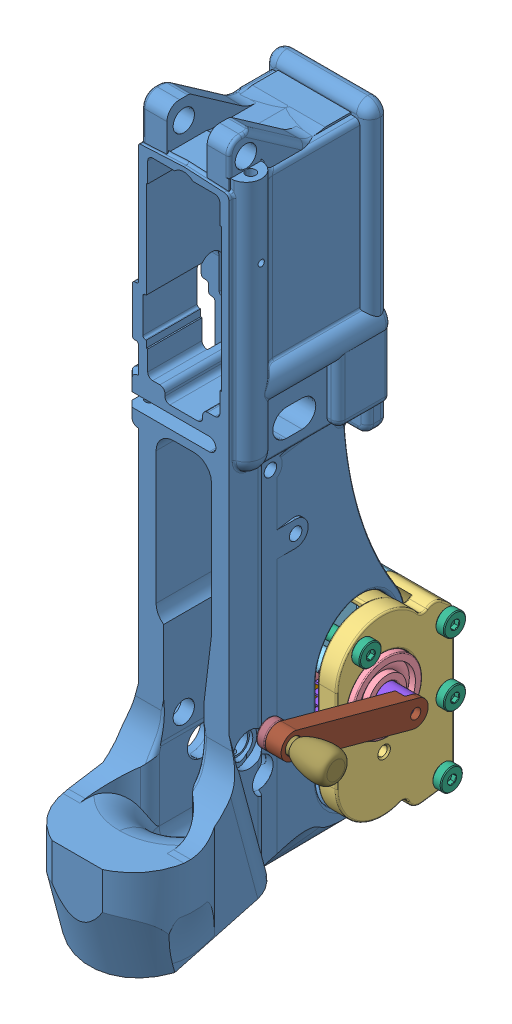
SolidWorks assembly full-assemble, configuration 默认. Lengths in mm.
Overall size (59.29 217.07 108.72).
17 component instances, 13 part files, 43 mates.
Components (placement in the parent):
- MKIIb_Reciever-1: MKIIb_Reciever [默认] at (-34.8208 26.1891 156.3421) size (38.84 217.07 108.72)
- LongTrigger-Straight.step-1: LongTrigger-Straight.step [默认] at (-5.1486 -10.3202 205.3271) x (0 -0.999998 0.002218) z (1 0 0) size (101.01 24.9 16.87)
- Part3-3: Part3 [默认<As Machined>] at (-5.1451 0 0) x (0 0 -1) z (1 0 0) size (37.18 58.07 16)
- instrument ball bearing_68_am-1: instrument ball bearing_68_am [AFBMA 12.1.4.1 - 0080-22 - 8,SI,NC,8_68] at (8.8549 -72.7458 189.2413) x (1 0 0) z (0 -0.317918 0.948118) size (7 22 22)
- Part4-2: Part4 [默认] at (-5.1451 0 0) x (0 0 -1) z (1 0 0) size (37.18 58.07 22.13)
- 92855A428_18-8 Stainless Steel Low-Profile Socket Head Screws-1: 92855A428_18-8 Stainless Steel Low-Profile Socket Head Screws [92855A428] at (-5.2451 -104.2418 170.0652) x (0 -0.350043 -0.936734) z (1 0 0) size (7 7 38.29)
- 92855A428_18-8 Stainless Steel Low-Profile Socket Head Screws-2: 92855A428_18-8 Stainless Steel Low-Profile Socket Head Screws [92855A428] at (-5.2451 -82.3598 169.0652) x (0 -0.001925 -0.999998) z (1 0 0) size (7 7 38.29)
- 92855A428_18-8 Stainless Steel Low-Profile Socket Head Screws-3: 92855A428_18-8 Stainless Steel Low-Profile Socket Head Screws [92855A428] at (-5.2451 -62.3598 169.0652) x (0 0.933702 0.358051) z (1 0 0) size (7 7 38.29)
- 92855A428_18-8 Stainless Steel Low-Profile Socket Head Screws-4: 92855A428_18-8 Stainless Steel Low-Profile Socket Head Screws [92855A428] at (-5.2451 -57.3338 195.7413) x (0 -0.893253 0.449554) z (1 0 0) size (7 7 38.29)
- rod-1: rod [默认] at (-6.6486 -88.4933 194.5525) x (0 -0.97624 -0.216692) z (0 -0.216692 0.97624) size (5 3 19)
- big-gear-4: big-gear [Metric - Spur gear 0.8M 30T 20PA 5.5FW ---S30O3.8H11L0.8N] at (4.3549 -72.7458 189.2413) x (-1 0 0) z (0 -0.965125 0.261791) size (18 25.5 25.6)
- instrument ball bearing_68_am-2: instrument ball bearing_68_am [AFBMA 12.1.4.1 - 0080-22 - 8,SI,NC,8_68] at (-17.6451 -88.7379 188.7413) x (1 0 0) z (0 0.211103 0.977464) size (7 22 22)
- pod-1: pod [默认] at (-21.6486 -88.7379 188.7413) x (0 -0.854815 -0.518933) z (0 -0.518933 0.854815) size (12 15 12)
- hexgon-3: hexgon [Metric - Spur gear 0.8M 10T 20PA 8FW ---S10O3.8H18L0.8N] at (9.3549 -88.7379 188.7413) x (-1 0 0) z (0 -0.518933 0.854815) size (8 12 12)
- crank-3: crank [默认] at (16.3549 -72.7458 189.2413) x (0 0.261791 0.965125) z (0 0.965125 -0.261791) size (47.9 5 7.9)
- handle-3: handle [默认] at (13.3549 -62.2741 227.8463) x (0 -0.8276 -0.561319) z (0 -0.561319 0.8276) size (13.32 21.38 13.32)
- handle_flange-2: handle_flange [默认] at (16.3549 -62.2741 227.8463) x (0 -0.8276 -0.561319) z (0 0.561319 -0.8276) size (7.9 3 7.9)
Mates (geometry in assembly coordinates):
- Concentric1: concentric anti-aligned: circle of MKIIb_Reciever-1; circle of LongTrigger-Straight.step-1
- Distance1: distance = 1.755 mm anti-aligned: plane of MKIIb_Reciever-1 through (3.6168 -15.8854 204.3318) normal (-1 0 0); plane of LongTrigger-Straight.step-1 through (1.8618 -19.4922 212.2058) normal (1 0 0)
- Concentric3: concentric anti-aligned: cylinder of MKIIb_Reciever-1 through (-16.6524 -91.6577 189.1532) axis (1 0 0) radius 14.5881; cylinder of Part3-3 through (4.8549 -91.6577 189.1532) axis (-1 0 0) radius 14.5881
- Concentric10: concentric anti-aligned: cylinder of Part3-3 through (14.8549 -72.7458 189.2413) axis (-1 0 0) radius 11.1; cylinder of instrument ball bearing_68_am-1 through (-11.7826 -72.7458 189.2413) axis (1 0 0) radius 11
- Distance8: distance = 5.065 mm: plane of Part3-3 through (-5.1451 0 0) normal (-1 0 0); line of MKIIb_Reciever-1 through (-0.0801 -91.6577 171.5652) axis (0 1 0)
- Concentric12: concentric aligned: cylinder of MKIIb_Reciever-1 through (-16.6524 -65.3338 189.1532) axis (1 0 0) radius 14.5881; circle of Part3-1
- Coincident14: coincident anti-aligned: plane of Part3-3 through (5.3549 -72.7458 189.2413) normal (1 0 0); plane of instrument ball bearing_68_am-1 through (5.3549 -64.3075 192.0708) normal (-1 0 0)
- Coincident15: coincident anti-aligned: plane of Part3-3 through (-5.1451 0 0) normal (-1 0 0); plane of Part4-2 through (-5.1451 0 0) normal (1 0 0)
- Concentric25: concentric anti-aligned: cylinder of Part3-3 through (10.8549 -104.2418 170.0652) axis (-1 0 0) radius 2.05; cylinder of 92855A428_18-8 Stainless Steel Low-Profile Socket Head Screws-1 through (12.2549 -104.2418 170.0652) axis (1 0 0) radius 2
- Coincident31: coincident anti-aligned: plane of Part3-3 through (10.8549 -91.6577 189.1532) normal (1 0 0); plane of 92855A428_18-8 Stainless Steel Low-Profile Socket Head Screws-1 through (10.8549 -102.181 169.2951) normal (-1 0 0)
- Concentric26: concentric anti-aligned: cylinder of Part3-3 through (10.8549 -62.3598 169.0652) axis (-1 0 0) radius 2.05; cylinder of 92855A428_18-8 Stainless Steel Low-Profile Socket Head Screws-3 through (12.2549 -62.3598 169.0652) axis (1 0 0) radius 2
- Concentric27: concentric anti-aligned: cylinder of Part3-3 through (10.8549 -82.3598 169.0652) axis (-1 0 0) radius 2.05; cylinder of 92855A428_18-8 Stainless Steel Low-Profile Socket Head Screws-2 through (12.2549 -82.3598 169.0652) axis (1 0 0) radius 2
- Coincident32: coincident anti-aligned: plane of 92855A428_18-8 Stainless Steel Low-Profile Socket Head Screws-3 through (10.8549 -63.1475 171.1193) normal (-1 0 0); plane of Part3-3 through (10.8549 -91.6577 189.1532) normal (1 0 0)
- Coincident33: coincident anti-aligned: plane of Part3-3 through (10.8549 -91.6577 189.1532) normal (1 0 0); plane of 92855A428_18-8 Stainless Steel Low-Profile Socket Head Screws-2 through (10.8549 -80.1598 169.0609) normal (-1 0 0)
- Concentric31: concentric aligned: circle of Part4-2; cylinder of 92855A428_18-8 Stainless Steel Low-Profile Socket Head Screws-2 through (12.2549 -82.3598 169.0652) axis (1 0 0) radius 2
- Concentric32: concentric anti-aligned: cylinder of Part4-2 through (10.8549 -104.2418 170.0652) axis (-1 0 0) radius 2.05; cylinder of 92855A428_18-8 Stainless Steel Low-Profile Socket Head Screws-1 through (12.2549 -104.2418 170.0652) axis (1 0 0) radius 2
- Concentric54: concentric aligned: cylinder of Part4-2 through (-21.1451 -57.3338 195.7413) axis (1 0 0) radius 2.05; cylinder of 92855A428_18-8 Stainless Steel Low-Profile Socket Head Screws-4 through (12.2549 -57.3338 195.7413) axis (1 0 0) radius 2
- Coincident48: coincident anti-aligned: plane of Part3-3 through (10.8549 -91.6577 189.1532) normal (1 0 0); plane of 92855A428_18-8 Stainless Steel Low-Profile Socket Head Screws-4 through (10.8549 -58.3228 193.7761) normal (-1 0 0)
- Concentric62: concentric aligned: cylinder of Part3-3 through (6.8549 -88.7379 188.7413) axis (1 0 0) radius 1.5; cylinder of hexgon-2 through (-24.1451 -88.7379 189.7413) axis (1 0 0) radius 1.5
- Concentric70: concentric anti-aligned: cylinder of LongTrigger-Straight.step-1 through (-12.9656 -90.111 199.6732) axis (1 0 0) radius 1.5; cylinder of rod-1 through (-3.6486 -90.111 199.6732) axis (-1 0 0) radius 1.5
- Distance20: distance = 0.5 mm anti-aligned: plane of big-gear-4 through (4.3549 -72.7458 189.2413) normal (1 0 0); plane of Part3-3 through (4.8549 -91.6577 189.1532) normal (-1 0 0)
- Concentric75: concentric anti-aligned: cylinder of instrument ball bearing_68_am-1 through (-11.7826 -72.7458 189.2413) axis (1 0 0) radius 4; cylinder of big-gear-4 through (19.3549 -72.7458 189.2413) axis (-1 0 0) radius 3.9
- Concentric76: concentric anti-aligned: cylinder of Part3-3 through (14.8549 -88.7379 188.7413) axis (-1 0 0) radius 1.6; cylinder of instrument ball bearing_68_am-2 through (-38.2826 -88.7379 188.7413) axis (1 0 0) radius 4
- Coincident63: coincident aligned: plane of Part4-2 through (-21.1451 -91.6577 189.1532) normal (-1 0 0); plane of instrument ball bearing_68_am-2 through (-21.1451 -80.0385 186.8625) normal (-1 0 0)
- Concentric77: concentric aligned: cylinder of instrument ball bearing_68_am-2 through (-38.2826 -88.7379 188.7413) axis (1 0 0) radius 4; cylinder of hexgon-2 through (-7.1451 -88.7379 189.7413) axis (1 0 0) radius 10
- Concentric78: concentric aligned: cylinder of rod-1 through (-3.6486 -87.0774 186.0059) axis (-1 0 0) radius 1.5; cylinder of hexgon-2 through (-3.1451 -91.8291 190.5688) axis (-1 0 0) radius 1.1
- Concentric79: concentric anti-aligned: cylinder of instrument ball bearing_68_am-2 through (-38.2826 -88.7379 188.7413) axis (1 0 0) radius 4; cylinder of pod-1 through (-14.1486 -88.7379 188.7413) axis (-1 0 0) radius 3.9
- Concentric82: concentric aligned: cylinder of rod-1 through (-3.6486 -87.0774 186.0059) axis (-1 0 0) radius 1.5; cylinder of pod-1 through (-6.6486 -87.0774 186.0059) axis (-1 0 0) radius 1.6
- Coincident64: coincident anti-aligned: plane of rod-1 through (-6.6486 -88.4933 194.5525) normal (-1 0 0); plane of pod-1 through (-6.6486 -88.7379 188.7413) normal (1 0 0)
- Coincident65: coincident aligned: plane of big-gear-4 through (4.3549 -72.7458 189.2413) normal (1 0 0); plane of hexgon-2 through (3.8549 -90.6173 189.7311) normal (1 0 0)
- Concentric83: concentric aligned: cylinder of Part3-3 through (6.8549 -88.7379 188.7413) axis (1 0 0) radius 1.5; cylinder of hexgon-3 through (-2.6451 -88.7379 188.7413) axis (1 0 0) radius 1.5
- Coincident66: coincident aligned: plane of big-gear-4 through (4.3549 -72.7458 189.2413) normal (1 0 0); plane of hexgon-3 through (4.3549 -87.3734 187.449) normal (1 0 0)
- Concentric84: concentric aligned: cylinder of rod-1 through (-3.6486 -87.0774 186.0059) axis (-1 0 0) radius 1.5; circle of hexgon-3
- Concentric85: concentric anti-aligned: circle of big-gear-4; circle of crank-3
- Parallel14: parallel anti-aligned: plane of big-gear-4 through (16.3549 -69.198 190.861) normal (0 0.261791 0.965125); plane of crank-3 through (19.3549 -69.1777 190.9358) normal (0 -0.261791 -0.965125)
- Coincident68: coincident anti-aligned: plane of big-gear-4 through (19.3549 -72.7458 189.2413) normal (1 0 0); plane of crank-3 through (19.3549 -72.7458 189.2413) normal (-1 0 0)
- Concentric86: concentric anti-aligned: cylinder of crank-3 through (21.3549 -62.2741 227.8463) axis (-1 0 0) radius 2.6; cylinder of handle-3 through (34.7317 -62.2741 227.8463) axis (1 0 0) radius 2.4
- Coincident69: coincident anti-aligned: plane of crank-3 through (16.3549 -72.7458 189.2413) normal (-1 0 0); plane of handle_flange-2 through (16.3549 -62.2741 227.8463) normal (1 0 0)
- Concentric87: concentric aligned: cylinder of handle-3 through (34.7317 -62.2741 227.8463) axis (1 0 0) radius 2.4; cylinder of handle_flange-2 through (13.3549 -62.2741 227.8463) axis (1 0 0) radius 2.55
- Parallel16: parallel anti-aligned: plane of handle-3 through (16.3549 -59.8816 227.6565) normal (0 0.561319 -0.8276); plane of handle_flange-2 through (13.3549 -59.7327 227.6366) normal (0 -0.561319 0.8276)
- Coincident72: coincident aligned: plane of handle-3 through (13.3549 -62.2741 227.8463) normal (-1 0 0); plane of handle_flange-2 through (13.3549 -62.2741 227.8463) normal (-1 0 0)
- GearMate2: gear = 21.998 : 5.998 mm: cylinder of hexgon-3 through (1.3549 -88.7379 188.7413) axis (1 0 0) radius 2.999; cylinder of big-gear-4 through (-1.1451 -72.7458 189.2413) axis (1 0 0) radius 10.999
- Distance21: distance = 0.05 mm anti-aligned: plane of rod-1 through (-6.6486 -88.4933 194.5525) normal (-1 0 0); plane of LongTrigger-Straight.step-1 through (-6.6986 -85.3258 202.8773) normal (1 0 0)
